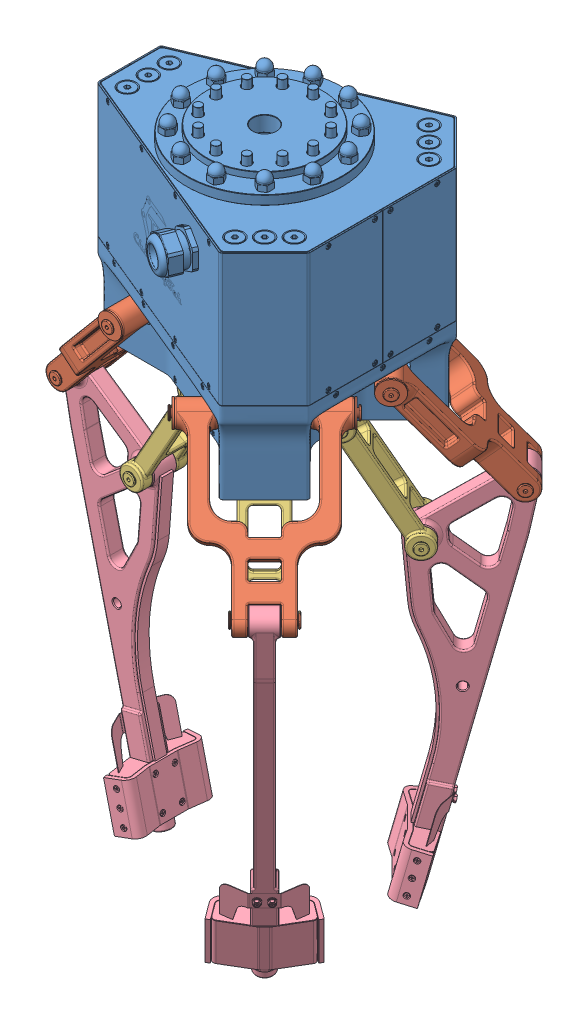
SolidWorks assembly CTHM3F460_三指重型模块化手(无传感器), configuration 默认. Lengths in mm.
Overall size (519.9 869.55 503.52).
10 component instances, 4 part files, 27 mates.
Components (placement in the parent):
- CTM3F460.01_基座外壳组件-1: CTM3F460.01_基座外壳组件 [默认] at origin size (329.89 347.93 319.01)
- CTM6F460.02.02.01.01_驱动臂组件-1: CTM6F460.02.02.01.01_驱动臂组件 [默认] at (-115 -55 0) x (0 0 1) z (-0.690276 -0.723546 0) size (175.8 43.55 219.61)
- CTM6F460.02.02.01.01_驱动臂组件-2: CTM6F460.02.02.01.01_驱动臂组件 [默认] at (81.3173 -55 81.3173) x (0.707107 0 -0.707107) z (0.488099 -0.723546 0.488099) size (175.8 43.55 219.61)
- CTM6F460.02.02.01.01_驱动臂组件-4: CTM6F460.02.02.01.01_驱动臂组件 [默认] at (81.3173 -55 -81.3173) x (-0.707107 0 -0.707107) z (0.488099 -0.723546 -0.488099) size (175.8 43.55 219.61)
- CTM6F460.02.02.01.02_从动臂组件-1: CTM6F460.02.02.01.02_从动臂组件 [默认] at (-193.2967 -188.3874 0) x (0 0 -1) z (0.444368 0.895844 0) size (65.8 38.07 179.78)
- CTM6F460.02.02.01.02_从动臂组件-2: CTM6F460.02.02.01.02_从动臂组件 [默认] at (136.6814 -188.3874 136.6814) x (-0.707107 0 0.707107) z (-0.314216 0.895844 -0.314216) size (65.8 38.07 179.78)
- CTM6F460.02.02.01.02_从动臂组件-4: CTM6F460.02.02.01.02_从动臂组件 [默认] at (35.2423 -269.4479 -35.2423) x (-0.707107 0 -0.707107) z (-0.380496 0.84288 0.380496) size (65.8 38.07 179.78)
- CTM6F460.02.02.01.03_手指指端组件-1: CTM6F460.02.02.01.03_手指指端组件 [默认] at (-55.5384 -144.6502 0) x (0 0 1) z (-0.99291 -0.118871 0) size (108.42 487.59 119.45)
- CTM6F460.02.02.01.03_手指指端组件-2: CTM6F460.02.02.01.03_手指指端组件 [默认] at (39.2716 -144.6502 39.2716) x (0.707107 0 -0.707107) z (0.702093 -0.118871 0.702093) size (108.42 487.59 119.45)
- CTM6F460.02.02.01.03_手指指端组件-6: CTM6F460.02.02.01.03_手指指端组件 [默认] at (39.2716 -144.6502 -39.2716) x (-0.707107 0 -0.707107) z (0.702093 -0.118871 -0.702093) size (108.42 487.59 119.45)
Mates (geometry in assembly coordinates):
- 重合1: coincident aligned: plane of CTM3F460.01_基座外壳组件-1 through (0 0 0) normal (0 0 1); plane of assembly through (0 0 0) normal (0 0 1)
- 重合2: coincident aligned: plane of CTM3F460.01_基座外壳组件-1 through (0 0 0) normal (0 1 0); plane of assembly through (0 0 0) normal (0 1 0)
- 重合3: coincident aligned: plane of CTM3F460.01_基座外壳组件-1 through (0 0 0) normal (1 0 0); plane of assembly through (0 0 0) normal (1 0 0)
- 同心1: concentric aligned: cylinder of CTM3F460.01_基座外壳组件-1 through (-115 -55 82) axis (0 0 1) radius 9; cylinder of CTM6F460.02.02.01.01_驱动臂组件-1 through (-115 -55 0) axis (0 0 1) radius 9
- 宽度1: width aligned: plane of CTM6F460.02.02.01.01_驱动臂组件-1 through (-115 -55 -42) normal (0 0 1); plane of CTM6F460.02.02.01.01_驱动臂组件-1 through (-115 -55 42) normal (0 0 -1); plane of CTM3F460.01_基座外壳组件-1 through (-115 -55 42) normal (0 0 1); plane of CTM3F460.01_基座外壳组件-1 through (-115 -55 -42) normal (0 0 -1)
- 同心2: concentric anti-aligned: cylinder of CTM3F460.01_基座外壳组件-1 through (-68.5 -135 15) axis (0 0 -1) radius 15; cylinder of CTM6F460.02.02.01.02_从动臂组件-1 through (-68.5 -135 -30) axis (0 0 1) radius 15
- 宽度2: width anti-aligned: plane of CTM6F460.02.02.01.02_从动臂组件-1 through (-48.0614 -129.3199 15.25) normal (0 0 -1); plane of CTM6F460.02.02.01.02_从动臂组件-1 through (-48.0614 -129.3199 -15.25) normal (0 0 1); plane of CTM3F460.01_基座外壳组件-1 through (-53.5 -150 15) normal (0 0 1); plane of CTM3F460.01_基座外壳组件-1 through (-53.5 -150 -15) normal (0 0 -1)
- 同心3: concentric aligned: cylinder of CTM6F460.02.02.01.01_驱动臂组件-1 through (-237.1296 -200.5484 0) axis (0 0 1) radius 15; cylinder of CTM6F460.02.02.01.03_手指指端组件-1 through (-237.1296 -200.5484 -10) axis (0 0 1) radius 8
- 同心4: concentric aligned: cylinder of CTM6F460.02.02.01.02_从动臂组件-1 through (-142.2923 -265.5936 -30) axis (0 0 1) radius 15; cylinder of CTM6F460.02.02.01.03_手指指端组件-1 through (-142.2923 -265.5936 -10) axis (0 0 1) radius 8
- 宽度3: width anti-aligned: plane of CTM6F460.02.02.01.01_驱动臂组件-1 through (-115 -55 -15.25) normal (0 0 1); plane of CTM6F460.02.02.01.01_驱动臂组件-1 through (-115 -55 15.25) normal (0 0 -1); plane of CTM6F460.02.02.01.03_手指指端组件-1 through (-237.1296 -200.5484 -15) normal (0 0 -1); plane of CTM6F460.02.02.01.03_手指指端组件-1 through (-237.1296 -200.5484 15) normal (0 0 1)
- 同心5: concentric aligned: cylinder of CTM3F460.01_基座外壳组件-1 through (139.3 -55 23.3345) axis (0.707107 0 -0.707107) radius 9; cylinder of CTM6F460.02.02.01.01_驱动臂组件-2 through (81.3173 -55 81.3173) axis (0.707107 0 -0.707107) radius 9
- 宽度4: width anti-aligned: plane of CTM6F460.02.02.01.01_驱动臂组件-2 through (51.6188 -55 111.0158) normal (0.707107 0 -0.707107); plane of CTM6F460.02.02.01.01_驱动臂组件-2 through (111.0158 -55 51.6188) normal (-0.707107 0 0.707107); plane of CTM3F460.01_基座外壳组件-1 through (51.6188 -55 111.0158) normal (-0.707107 0 0.707107); plane of CTM3F460.01_基座外壳组件-1 through (111.0158 -55 51.6188) normal (0.707107 0 -0.707107)
- 同心6: concentric aligned: cylinder of CTM3F460.01_基座外壳组件-1 through (23.3345 -55 -139.3) axis (-0.707107 0 -0.707107) radius 9; cylinder of CTM6F460.02.02.01.01_驱动臂组件-4 through (81.3173 -55 -81.3173) axis (-0.707107 0 -0.707107) radius 9
- 宽度5: width anti-aligned: plane of CTM6F460.02.02.01.01_驱动臂组件-4 through (111.0158 -55 -51.6188) normal (-0.707107 0 -0.707107); plane of CTM6F460.02.02.01.01_驱动臂组件-4 through (51.6188 -55 -111.0158) normal (0.707107 0 0.707107); plane of CTM3F460.01_基座外壳组件-1 through (111.0158 -55 -51.6188) normal (0.707107 0 0.707107); plane of CTM3F460.01_基座外壳组件-1 through (51.6188 -55 -111.0158) normal (-0.707107 0 -0.707107)
- 同心7: concentric anti-aligned: cylinder of CTM3F460.01_基座外壳组件-1 through (59.0434 -135 37.8302) axis (-0.707107 0 0.707107) radius 15; cylinder of CTM6F460.02.02.01.02_从动臂组件-2 through (27.2236 -135 69.65) axis (0.707107 0 -0.707107) radius 15
- 宽度6: width anti-aligned: plane of CTM6F460.02.02.01.02_从动臂组件-2 through (44.7679 -129.3199 23.2012) normal (-0.707107 0 0.707107); plane of CTM6F460.02.02.01.02_从动臂组件-2 through (23.2012 -129.3199 44.7679) normal (0.707107 0 -0.707107); plane of CTM3F460.01_基座外壳组件-1 through (27.2236 -150 48.4368) normal (-0.707107 0 0.707107); plane of CTM3F460.01_基座外壳组件-1 through (48.4368 -150 27.2236) normal (0.707107 0 -0.707107)
- 同心8: concentric anti-aligned: cylinder of CTM3F460.01_基座外壳组件-1 through (61.1647 -135 -35.7089) axis (-0.707107 0 -0.707107) radius 8; cylinder of CTM6F460.02.02.01.02_从动臂组件-4 through (27.2236 -135 -69.65) axis (0.707107 0 0.707107) radius 15
- 宽度7: width aligned: plane of CTM6F460.02.02.01.02_从动臂组件-4 through (63.2367 -114.5614 -41.6699) normal (-0.707107 0 -0.707107); plane of CTM6F460.02.02.01.02_从动臂组件-4 through (41.6699 -114.5614 -63.2367) normal (0.707107 0 0.707107); plane of CTM3F460.01_基座外壳组件-1 through (27.2236 -150 -48.4368) normal (-0.707107 0 -0.707107); plane of CTM3F460.01_基座外壳组件-1 through (48.4368 -150 -27.2236) normal (0.707107 0 0.707107)
- 同心9: concentric anti-aligned: cylinder of CTM6F460.02.02.01.01_驱动臂组件-2 through (167.676 -200.5484 167.676) axis (-0.707107 0 0.707107) radius 15; cylinder of CTM6F460.02.02.01.03_手指指端组件-2 through (160.6049 -200.5484 174.747) axis (0.707107 0 -0.707107) radius 8
- 同心10: concentric aligned: cylinder of CTM6F460.02.02.01.02_从动臂组件-2 through (79.4026 -265.5936 121.829) axis (0.707107 0 -0.707107) radius 15; cylinder of CTM6F460.02.02.01.03_手指指端组件-2 through (93.5448 -265.5936 107.6869) axis (0.707107 0 -0.707107) radius 8
- 宽度8: width aligned: plane of CTM6F460.02.02.01.01_驱动臂组件-2 through (92.1007 -55 70.5339) normal (-0.707107 0 0.707107); plane of CTM6F460.02.02.01.01_驱动臂组件-2 through (70.5339 -55 92.1007) normal (0.707107 0 -0.707107); plane of CTM6F460.02.02.01.03_手指指端组件-2 through (157.0694 -200.5484 178.2826) normal (-0.707107 0 0.707107); plane of CTM6F460.02.02.01.03_手指指端组件-2 through (178.2826 -200.5484 157.0694) normal (0.707107 0 -0.707107)
- 同心13: concentric anti-aligned: cylinder of CTM6F460.02.02.01.01_驱动臂组件-4 through (167.676 -200.5484 -167.676) axis (0.707107 0 0.707107) radius 15; cylinder of CTM6F460.02.02.01.03_手指指端组件-6 through (174.747 -200.5484 -160.6049) axis (-0.707107 0 -0.707107) radius 8
- 宽度10: width anti-aligned: plane of CTM6F460.02.02.01.01_驱动臂组件-4 through (70.5339 -55 -92.1007) normal (0.707107 0 0.707107); plane of CTM6F460.02.02.01.01_驱动臂组件-4 through (92.1007 -55 -70.5339) normal (-0.707107 0 -0.707107); plane of CTM6F460.02.02.01.03_手指指端组件-6 through (178.2826 -200.5484 -157.0694) normal (0.707107 0 0.707107); plane of CTM6F460.02.02.01.03_手指指端组件-6 through (157.0694 -200.5484 -178.2826) normal (-0.707107 0 -0.707107)
- 同心15: concentric anti-aligned: cylinder of CTM6F460.02.02.01.02_从动臂组件-4 through (79.4026 -265.5936 -121.829) axis (0.707107 0 0.707107) radius 15; cylinder of CTM6F460.02.02.01.03_手指指端组件-6 through (107.6869 -265.5936 -93.5448) axis (-0.707107 0 -0.707107) radius 8
- LimitAngle1: limit planar angle = 2.443461 rad anti-aligned: plane of CTM6F460.02.02.01.01_驱动臂组件-1 through (-126.4907 -45.3582 0) normal (-0.766044 0.642788 0); plane of CTM3F460.01_基座外壳组件-1 through (-174.632 -5 0) normal (-1 0 0)
- 对称1: symmetric aligned: plane of CTM6F460.02.02.01.01_驱动臂组件-1 through (-103.5093 -64.6418 0) normal (0.766044 -0.642788 0); plane of CTM6F460.02.02.01.01_驱动臂组件-2 through (73.1922 -64.6418 73.1922) normal (-0.541675 -0.642788 -0.541675); plane of assembly through (0 0 0) normal (-0.92388 0 -0.382683)
- 对称2: symmetric aligned: plane of CTM6F460.02.02.01.01_驱动臂组件-2 through (89.4424 -45.3582 89.4424) normal (0.541675 0.642788 0.541675); plane of CTM6F460.02.02.01.01_驱动臂组件-4 through (89.4424 -45.3582 -89.4424) normal (0.541675 0.642788 -0.541675); plane of assembly through (0 0 0) normal (0 0 1)
